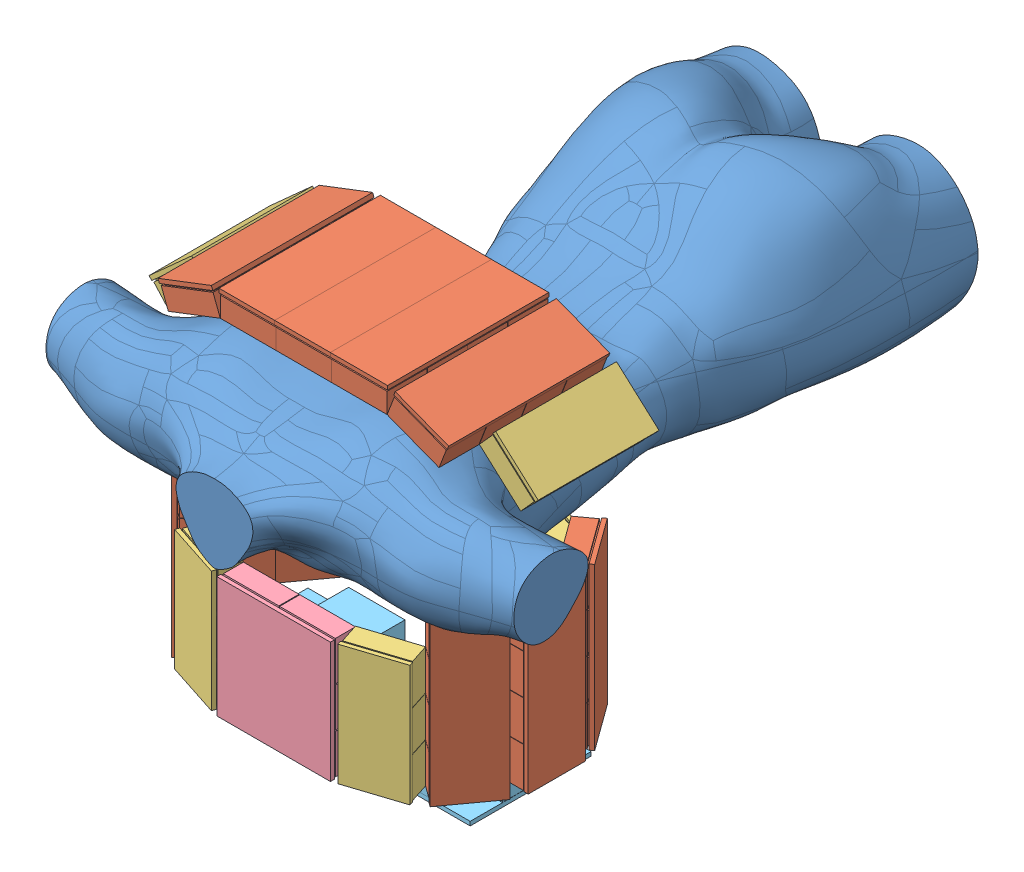
SolidWorks assembly BODYdetector, configuration Default. Lengths in mm.
Overall size (637.83 457.49 817.55).
26 component instances, 5 part files, 0 mates.
Components (placement in the parent):
- woman body-1: woman body [Default] at (325.4407 484.4544 221.086) size (637.83 301.02 817.55)
- Detector_posterial-1: Detector_posterial [Default] at (222.7152 725.2068 938.4124) x (1 0 0) z (0 0 -1) size (482.7 103.57 200)
  - 1Detector-1: 1Detector [Default] at (83.9721 85.3161 150.6758) size (71 32 200)
  - 1Detector-2: 1Detector [Default] at (152.9721 85.3161 150.6758) size (71 32 200)
  - 1Detector-3: 1Detector [Default] at (14.9721 85.3161 150.6758) size (71 32 200)
  - 1Detector-4: 1Detector [Default] at (-63.2042 99.8052 150.6758) x (0.93358 -0.358368 0) z (0 0 1) size (71 32 200)
  - 1Detector-5: 1Detector [Default] at (231.1484 99.8052 150.6758) x (0.93358 0.358368 0) z (0 0 1) size (71 32 200)
  - 1Detector_3modules-1: 1Detector_3modules [Default] at (-130.9957 141.3479 175.6758) x (0.743145 -0.669131 0) z (0 0 1) size (71 32 150)
  - 1Detector_3modules-2: 1Detector_3modules [Default] at (298.9398 141.3479 175.6758) x (0.743145 0.669131 0) z (0 0 1) size (71 32 150)
- Detector1n2_2-1: Detector1n2_2 [Default] at (262.1834 410.9569 572.8392) x (1 0 0) z (0 -1 0) size (495.24 340.33 230.2)
  - top_bottomDetector2-1: top_bottomDetector2 [Default] at (5.3043 60.2155 74.3483) size (141 32 149.74)
  - CshapedDetector2-1: CshapedDetector2 [Default] at (104.3454 -76.5763 -85.899) x (0.951057 0.309017 0) z (0 0 1) size (177.89 270.84 200)
    - 1Detector-2: 1Detector [Default] at (173.0714 153.2337 184.2598) x (0.809017 0.587785 0) z (0 0 1) size (71 32 200)
    - 1Detector-4: 1Detector [Default] at (223.2683 222.3237 184.2598) x (0.309017 0.951057 0) z (0 0 1) size (71 32 200)
    - 1Detector-5: 1Detector [Default] at (223.2683 307.7237 184.2598) x (-0.309017 0.951057 0) z (0 0 1) size (71 32 200)
    - 1Detector_3modules-1: 1Detector_3modules [Default] at (91.8512 126.8436 209.2598) size (71 32 150)
    - 1Detector_3modules-2: 1Detector_3modules [Default] at (173.0714 376.8138 209.2598) x (-0.809017 0.587785 0) z (0 0 1) size (71 32 150)
  - CshapedDetector2-2: CshapedDetector2 [Default] at (-23.7368 484.2959 -85.899) x (-0.951057 -0.309017 0) z (0 0 1) size (177.89 270.84 200)
    - 1Detector-2: 1Detector [Default] at (173.0714 153.2337 184.2598) x (0.809017 0.587785 0) z (0 0 1) size (71 32 200)
    - 1Detector-4: 1Detector [Default] at (223.2683 222.3237 184.2598) x (0.309017 0.951057 0) z (0 0 1) size (71 32 200)
    - 1Detector-5: 1Detector [Default] at (223.2683 307.7237 184.2598) x (-0.309017 0.951057 0) z (0 0 1) size (71 32 200)
    - 1Detector_3modules-1: 1Detector_3modules [Default] at (91.8512 126.8436 209.2598) size (71 32 150)
    - 1Detector_3modules-2: 1Detector_3modules [Default] at (173.0714 376.8138 209.2598) x (-0.809017 0.587785 0) z (0 0 1) size (71 32 150)
  - top_bottomDetector2-2: top_bottomDetector2 [Default] at (75.3043 347.5042 74.3483) x (-1 0 0) z (0 0 1) size (141 32 149.74)
  - Detector2-1: Detector2 [Default] at (-50.3758 204.3598 228.5608) x (1 0 0) z (0 1 0) size (170 30.5 151.04)
  - Detector2-2: Detector2 [Default] at (130.9844 204.3598 228.5608) x (1 0 0) z (0 1 0) size (170 30.5 151.04)
